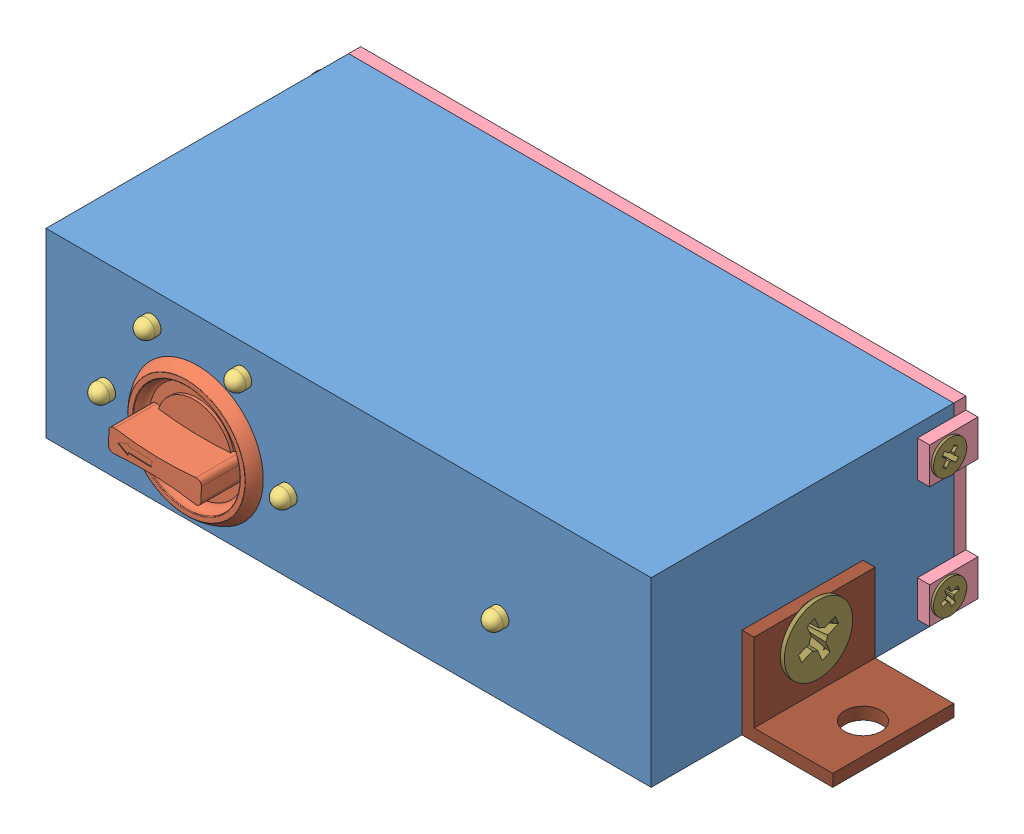
SolidWorks assembly VSD CONTROL PANAL ASSEMBLY, configuration Default. Lengths in mm.
Overall size (130 30.43 66.2).
46 component instances, 12 part files, 43 mates.
Components (placement in the parent):
- Revised Control Panel-1: Revised Control Panel [Default] at (43.0066 43.981 102.3357) size (100 30 50)
- Switch_19mm_Red-1: Switch_19mm_Red [Default] at (18.2589 48.8769 104.3357) x (0.031932 0.99949 0) z (0.99949 -0.031932 0) size (21.8 47 21.8)
- LED_3MM-1: LED_3MM [Predeterminado] at (3.0066 40.981 101.3357) x (1 0 0) z (0 -1 0) size (3.37 9.49 3.74)
- LED_3MM-2: LED_3MM [Predeterminado] at (10.5066 53.9713 101.3357) x (1 0 0) z (0 -1 0) size (3.37 9.49 3.74)
- LED_3MM-3: LED_3MM [Predeterminado] at (25.5066 53.9713 101.3357) x (1 0 0) z (0 -1 0) size (3.37 9.49 3.74)
- LED_3MM-4: LED_3MM [Predeterminado] at (33.0066 40.981 101.3357) x (1 0 0) z (0 -1 0) size (3.37 9.49 3.74)
- LED_3MM-5: LED_3MM [Predeterminado] at (68.0066 40.981 101.3357) x (0.78367 -0.621177 0) z (-0.621177 -0.78367 0) size (3.37 9.49 3.74)
- VSD Control Panel Back Panel-1: VSD Control Panel Back Panel [Default] at (43.0066 43.981 54.3357) x (-1 0 0) z (0 0 -1) size (104 30 8)
- D-tupe 9 pin female-1: D-tupe 9 pin female [Default] at (84.8354 20.366 73.3839) x (-1 0 0) z (0 0 -1) size (30.84 12.55 15.35)
  - D-type 2-1: D-type 2 [Default] at (13.8361 17.4152 21.5482) size (30.84 12.55 7.3)
  - D-type 1-1: D-type 1 [Default] at (13.8361 17.4152 21.5482) x (-1 0 0) z (0 0 -1) size (30.84 12.55 4.4)
  - D-type 3-1: D-type 3 [Default] at (13.8361 17.4152 17.6482) size (16.3 8.2 12.45)
  - D-type pin female-1: D-type pin female [Default] at (19.3761 18.8352 27.7482) x (-1 0 0) z (0 0 -1) size (1.6 1.6 14.86)
  - D-type pin female-2: D-type pin female [Default] at (16.6061 18.8352 27.7482) x (-1 0 0) z (0 0 -1) size (1.6 1.6 14.86)
  - D-type pin female-3: D-type pin female [Default] at (13.8361 18.8352 27.7482) x (-1 0 0) z (0 0 -1) size (1.6 1.6 14.86)
  - D-type pin female-4: D-type pin female [Default] at (11.0661 18.8352 27.7482) x (-1 0 0) z (0 0 -1) size (1.6 1.6 14.86)
  - D-type pin female-5: D-type pin female [Default] at (8.2961 18.8352 27.7482) x (-1 0 0) z (0 0 -1) size (1.6 1.6 14.86)
  - D-type pin female-6: D-type pin female [Default] at (9.6855 15.9952 27.7482) x (1 0 0) z (0 0 -1) size (1.6 1.6 14.86)
  - D-type pin female-7: D-type pin female [Default] at (12.4555 15.9952 27.7482) x (1 0 0) z (0 0 -1) size (1.6 1.6 14.86)
  - D-type pin female-8: D-type pin female [Default] at (17.9955 15.9952 27.7482) x (1 0 0) z (0 0 -1) size (1.6 1.6 14.86)
  - D-type pin female-9: D-type pin female [Default] at (15.2255 15.9952 27.7482) x (1 0 0) z (0 0 -1) size (1.6 1.6 14.86)
- D-tupe 9 pin female-2: D-tupe 9 pin female [Default] at (52.9525 19.3658 73.3839) x (-1 0 0) z (0 0 -1) size (30.84 12.55 15.35)
  - D-type 2-1: D-type 2 [Default] at (13.8361 17.4152 21.5482) size (30.84 12.55 7.3)
  - D-type 1-1: D-type 1 [Default] at (13.8361 17.4152 21.5482) x (-1 0 0) z (0 0 -1) size (30.84 12.55 4.4)
  - D-type 3-1: D-type 3 [Default] at (13.8361 17.4152 17.6482) size (16.3 8.2 12.45)
  - D-type pin female-1: D-type pin female [Default] at (19.3761 18.8352 27.7482) x (-1 0 0) z (0 0 -1) size (1.6 1.6 14.86)
  - D-type pin female-2: D-type pin female [Default] at (16.6061 18.8352 27.7482) x (-1 0 0) z (0 0 -1) size (1.6 1.6 14.86)
  - D-type pin female-3: D-type pin female [Default] at (13.8361 18.8352 27.7482) x (-1 0 0) z (0 0 -1) size (1.6 1.6 14.86)
  - D-type pin female-4: D-type pin female [Default] at (11.0661 18.8352 27.7482) x (-1 0 0) z (0 0 -1) size (1.6 1.6 14.86)
  - D-type pin female-5: D-type pin female [Default] at (8.2961 18.8352 27.7482) x (-1 0 0) z (0 0 -1) size (1.6 1.6 14.86)
  - D-type pin female-6: D-type pin female [Default] at (9.6855 15.9952 27.7482) x (1 0 0) z (0 0 -1) size (1.6 1.6 14.86)
  - D-type pin female-7: D-type pin female [Default] at (12.4555 15.9952 27.7482) x (1 0 0) z (0 0 -1) size (1.6 1.6 14.86)
  - D-type pin female-8: D-type pin female [Default] at (17.9955 15.9952 27.7482) x (1 0 0) z (0 0 -1) size (1.6 1.6 14.86)
  - D-type pin female-9: D-type pin female [Default] at (15.2255 15.9952 27.7482) x (1 0 0) z (0 0 -1) size (1.6 1.6 14.86)
- DC Jack Panel Mount ASSY-1: DC Jack Panel Mount ASSY [Default] at (14.5761 36.781 49.0357) x (-1 0 0) z (0 0 -1) size (17.52 16.47 17.63)
  - DC Jack Panel Mount Base-1: DC Jack Panel Mount Base [Default] at origin size (10.2 10.2 17.63)
  - DC Jack Panel Mount Nut-1: DC Jack Panel Mount Nut [Default] at (0 0 -7.35) x (0.866025 -0.5 0) z (0 0 1) size (13.88 11 3.18)
- L bracket-1: L bracket [Default] at (-6.9934 28.981 89.3357) x (-1 0 0) z (0 0 -1) size (15 15 20)
- L bracket-2: L bracket [Default] at (28.8605 29.5101 61.8006) size (15 15 20)
- L bracket-3: L bracket [Default] at (93.0066 28.981 69.3357) size (15 15 20)
- countersunk flat head cross recess screw_bsi-2: countersunk flat head cross recess screw_bsi [BS EN ISO 7046-1 - M3 x 4 - Z - 4N] at (-9.3934 53.981 57.3357) size (4 5.5 5.5)
- countersunk flat head cross recess screw_bsi-3: countersunk flat head cross recess screw_bsi [BS EN ISO 7046-1 - M3 x 4 - Z - 4N] at (-9.3934 33.981 57.3357) size (4 5.5 5.5)
- countersunk flat head cross recess screw_bsi-5: countersunk flat head cross recess screw_bsi [BS EN ISO 7046-1 - M3 x 4 - Z - 4N] at (95.4066 33.981 57.3357) x (-1 0 0) z (0 -0.924225 -0.381849) size (4 5.5 5.5)
- countersunk flat head cross recess screw_bsi-6: countersunk flat head cross recess screw_bsi [BS EN ISO 7046-1 - M3 x 4 - Z - 4N] at (95.4066 53.981 57.3357) x (-1 0 0) z (0 -0.645189 -0.764023) size (4 5.5 5.5)
- countersunk flat head cross recess screw_bsi-7: countersunk flat head cross recess screw_bsi [BS EN ISO 7046-1 - M6 x 8 - Z - 8N] at (-9.6434 38.981 79.3357) size (8 11.3 11.3)
- countersunk flat head cross recess screw_bsi-8: countersunk flat head cross recess screw_bsi [BS EN ISO 7046-1 - M6 x 8 - Z - 8N] at (95.6566 38.981 79.3357) x (-1 0 0) z (0 -0.924225 -0.381849) size (8 11.3 11.3)
Mates (geometry in assembly coordinates):
- Concentric1: concentric: cylinder of Revised Control Panel-1 through (18.0066 40.981 104.3357) axis (0 0 -1) radius 9.5; cylinder of Switch_19mm_Red-1 through (18.0066 40.981 85.3357) axis (0 0 1) radius 9.5
- Coincident1: coincident anti-aligned: plane of Revised Control Panel-1 through (43.0066 43.981 104.3357) normal (0 0 1); plane of Switch_19mm_Red-1 through (18.2589 48.8769 104.3357) normal (0 0 -1)
- Coincident2: coincident aligned: circle of Revised Control Panel-1; plane of LED_3MM-5 through (66.5412 42.1426 102.3357) normal (0 0 1)
- Concentric2: concentric aligned: cylinder of Revised Control Panel-1 through (68.0066 40.981 104.3357) axis (0 0 -1) radius 1.5; circle of LED_3MM-5
- Coincident3: coincident: circle of Revised Control Panel-1; plane of LED_3MM-1 through (1.1366 40.981 102.3357) normal (0 0 1)
- Concentric3: concentric aligned: cylinder of Revised Control Panel-1 through (3.0066 40.981 104.3357) axis (0 0 -1) radius 1.5; cylinder of LED_3MM-1 through (3.0066 40.981 101.3357) axis (0 0 -1) radius 1.5
- Coincident4: coincident aligned: circle of Revised Control Panel-1; plane of LED_3MM-2 through (8.6366 53.9713 102.3357) normal (0 0 1)
- Concentric4: concentric aligned: cylinder of Revised Control Panel-1 through (10.5066 53.9713 104.3357) axis (0 0 -1) radius 1.5; cylinder of LED_3MM-2 through (10.5066 53.9713 101.3357) axis (0 0 -1) radius 1.5
- Coincident5: coincident aligned: circle of Revised Control Panel-1; plane of LED_3MM-3 through (23.6366 53.9713 102.3357) normal (0 0 1)
- Concentric5: concentric aligned: cylinder of Revised Control Panel-1 through (25.5066 53.9713 104.3357) axis (0 0 -1) radius 1.5; cylinder of LED_3MM-3 through (25.5066 53.9713 101.3357) axis (0 0 -1) radius 1.5
- Coincident6: coincident aligned: plane of Revised Control Panel-1 through (43.0066 43.981 102.3357) normal (0 0 -1); circle of LED_3MM-4
- Concentric6: concentric aligned: cylinder of Revised Control Panel-1 through (33.0066 40.981 104.3357) axis (0 0 -1) radius 1.5; cylinder of LED_3MM-4 through (33.0066 40.981 101.3357) axis (0 0 -1) radius 1.5
- Coincident7: coincident: plane of Revised Control Panel-1 through (43.0066 43.981 54.3357) normal (0 0 -1); line of VSD Control Panel Back Panel-1 through (-6.9934 58.981 54.3357) axis (1 0 0)
- Coincident8: coincident: line of Revised Control Panel-1 through (93.0066 58.981 104.3357) axis (0 0 -1); plane of VSD Control Panel Back Panel-1 through (93.0066 56.981 60.3357) normal (-1 0 0)
- Coincident9: coincident aligned: plane of Revised Control Panel-1 through (-6.9934 58.981 104.3357) normal (0 1 0); plane of VSD Control Panel Back Panel-1 through (93.0066 58.981 52.3357) normal (0 1 0)
- Coincident10: coincident anti-aligned: plane of VSD Control Panel Back Panel-1 through (43.0066 43.981 52.3357) normal (0 0 -1); plane of D-tupe 9 pin female-1/D-type 1-1 through (85.4193 43.0562 52.3357) normal (0 0 1)
- Concentric7: concentric aligned: cylinder of VSD Control Panel Back Panel-1 through (58.5043 37.7812 60.3367) axis (0 0 -1) radius 1.5; cylinder of D-tupe 9 pin female-1/D-type 2-1 through (58.5043 37.7812 56.149) axis (0 0 -1) radius 1.525
- Parallel1: parallel aligned: cylinder of VSD Control Panel Back Panel-1 through (83.5089 37.7812 60.3367) axis (0 0 -1) radius 1.5; cylinder of D-tupe 9 pin female-1/D-type 2-1 through (83.4943 37.7812 56.149) axis (0 0 -1) radius 1.525
- Concentric9: concentric aligned: cylinder of VSD Control Panel Back Panel-1 through (51.6114 36.781 60.3367) axis (0 0 -1) radius 1.5; cylinder of D-tupe 9 pin female-2/D-type 2-1 through (51.6114 36.781 56.149) axis (0 0 -1) radius 1.525
- Parallel2: parallel aligned: cylinder of VSD Control Panel Back Panel-1 through (26.6069 36.781 60.3367) axis (0 0 -1) radius 1.5; cylinder of D-tupe 9 pin female-2/D-type 2-1 through (26.6214 36.781 56.149) axis (0 0 -1) radius 1.525
- Coincident11: coincident anti-aligned: plane of VSD Control Panel Back Panel-1 through (43.0066 43.981 52.3357) normal (0 0 -1); plane of D-tupe 9 pin female-2/D-type 1-1 through (53.5364 42.056 52.3357) normal (0 0 1)
- Parallel6: parallel aligned: line of Revised Control Panel-1 through (93.0066 28.981 54.3357) axis (-1 0 0); line of D-tupe 9 pin female-2/D-type 2-1 through (53.5364 30.506 51.3357) axis (-1 0 0)
- Coincident13: coincident anti-aligned: plane of VSD Control Panel Back Panel-1 through (43.0066 43.981 52.3357) normal (0 0 -1); plane of DC Jack Panel Mount ASSY-1/DC Jack Panel Mount Base-1 through (9.4761 36.781 52.3357) normal (0 0 1)
- Concentric17: concentric aligned: cylinder of VSD Control Panel Back Panel-1 through (14.5761 36.781 60.3367) axis (0 0 -1) radius 4; cylinder of DC Jack Panel Mount ASSY-1/DC Jack Panel Mount Base-1 through (14.5761 36.781 49.0357) axis (0 0 -1) radius 5.1
- Concentric18: concentric aligned: cylinder of Revised Control Panel-1 through (93.0066 38.981 79.3357) axis (-1 0 0) radius 3; cylinder of L bracket-1 through (11.0066 38.981 79.3357) axis (-1 0 0) radius 3
- Coincident15: coincident anti-aligned: plane of Revised Control Panel-1 through (-6.9934 28.981 104.3357) normal (-1 0 0); plane of L bracket-1 through (-6.9934 43.981 69.3357) normal (1 0 0)
- Parallel8: parallel aligned: line of Revised Control Panel-1 through (-6.9934 58.981 104.3357) axis (0 -1 0); line of L bracket-1 through (-6.9934 43.981 89.3357) axis (0 -1 0)
- Coincident17: coincident anti-aligned: plane of Revised Control Panel-1 through (93.0066 28.981 104.3357) normal (1 0 0); plane of L bracket-3 through (93.0066 43.981 89.3357) normal (-1 0 0)
- Concentric19: concentric anti-aligned: cylinder of Revised Control Panel-1 through (93.0066 38.981 79.3357) axis (-1 0 0) radius 3; cylinder of L bracket-3 through (75.0066 38.981 79.3357) axis (1 0 0) radius 3
- Parallel9: parallel: line of Revised Control Panel-1 through (93.0066 28.981 104.3357) axis (0 1 0); plane of L bracket-3 through (93.0066 28.981 89.3357) normal (0 0 1)
- Concentric20: concentric aligned: cylinder of VSD Control Panel Back Panel-1 through (-8.9934 53.981 57.3357) axis (1 0 0) radius 1.5; cone of countersunk flat head cross recess screw_bsi-2 through (-8.9934 53.981 57.3357) axis (1 0 0)
- Concentric21: concentric aligned: cylinder of VSD Control Panel Back Panel-1 through (-8.9934 33.981 57.3357) axis (1 0 0) radius 1.5; cone of countersunk flat head cross recess screw_bsi-3 through (-8.9934 33.981 57.3357) axis (1 0 0)
- Concentric231: concentric aligned: cylinder of Revised Control Panel-1 through (93.0066 53.981 57.3357) axis (-1 0 0) radius 1.5; cone of countersunk flat head cross recess screw_bsi-6 through (95.0066 53.981 57.3357) axis (-1 0 0)
- Concentric24: concentric aligned: cylinder of VSD Control Panel Back Panel-1 through (-8.9934 33.981 57.3357) axis (1 0 0) radius 1.5; cylinder of countersunk flat head cross recess screw_bsi-5 through (101.7566 33.981 57.3357) axis (1 0 0) radius 1.5
- Coincident19: coincident aligned: plane of VSD Control Panel Back Panel-1 through (95.0066 36.981 60.3357) normal (1 0 0); circle of countersunk flat head cross recess screw_bsi-5
- Coincident20: coincident aligned: plane of VSD Control Panel Back Panel-1 through (95.0066 56.981 60.3357) normal (1 0 0); circle of countersunk flat head cross recess screw_bsi-6
- Coincident21: coincident aligned: plane of VSD Control Panel Back Panel-1 through (-8.9934 56.981 60.3357) normal (-1 0 0); circle of countersunk flat head cross recess screw_bsi-2
- Coincident22: coincident aligned: plane of VSD Control Panel Back Panel-1 through (-8.9934 36.981 60.3357) normal (-1 0 0); circle of countersunk flat head cross recess screw_bsi-3
- Concentric25: concentric: cylinder of Revised Control Panel-1 through (93.0066 38.981 79.3357) axis (-1 0 0) radius 3; cone of countersunk flat head cross recess screw_bsi-8 through (105.2002 38.981 79.3357) axis (-1 0 0)
- Coincident26: coincident aligned: plane of L bracket-1 through (-8.9934 30.981 69.3357) normal (-1 0 0); circle of countersunk flat head cross recess screw_bsi-7
- Concentric27: concentric aligned: cylinder of L bracket-1 through (11.0066 38.981 79.3357) axis (-1 0 0) radius 3; cylinder of countersunk flat head cross recess screw_bsi-7 through (-15.9934 38.981 79.3357) axis (-1 0 0) radius 5.65
- Concentric28: concentric: cylinder of L bracket-3 through (75.0066 38.981 79.3357) axis (1 0 0) radius 3; cylinder of countersunk flat head cross recess screw_bsi-8 through (102.0066 38.981 79.3357) axis (1 0 0) radius 3
- Coincident27: coincident aligned: plane of L bracket-3 through (95.0066 30.981 89.3357) normal (1 0 0); circle of countersunk flat head cross recess screw_bsi-8
